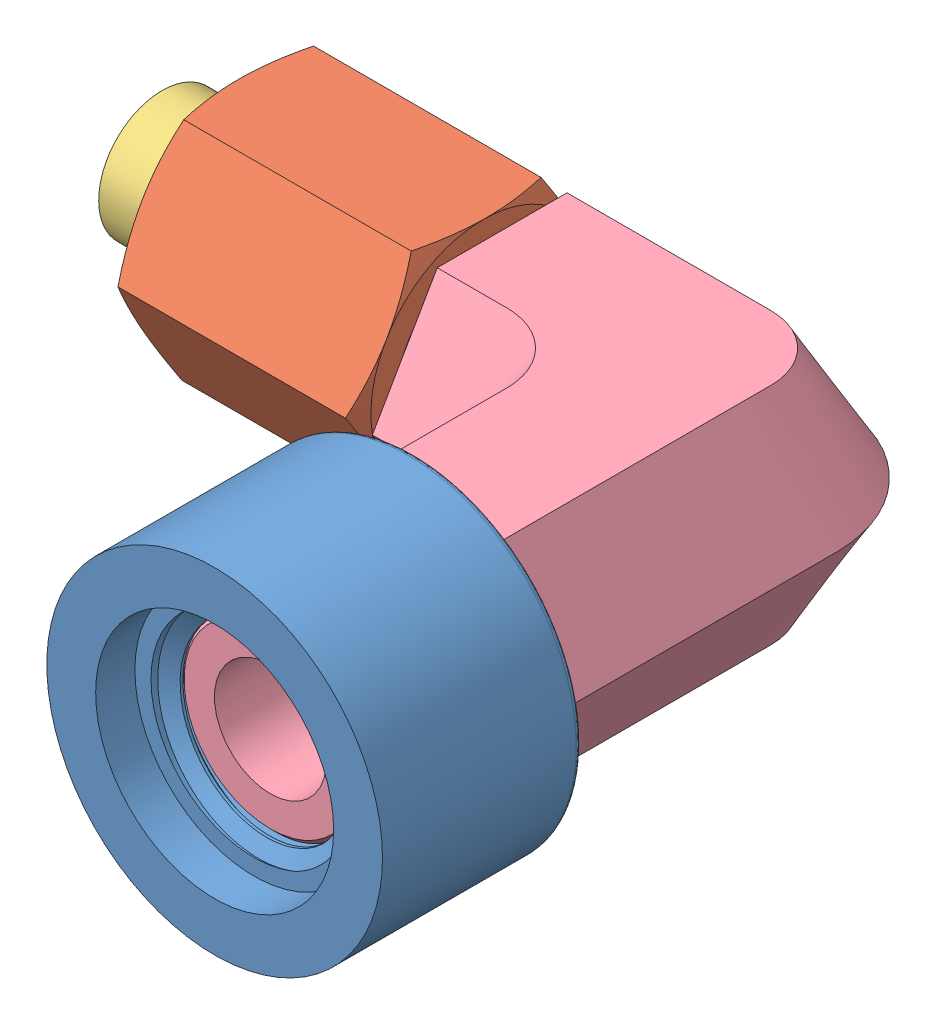
SolidWorks assembly Shroud Plumbing Connection Assem, configuration Default. Lengths in mm.
Overall size (45.23 21.34 39.53).
4 component instances, 4 part files, 9 mates.
Components (placement in the parent):
- 4452K139_TYPE 316 STAINLESS STL THREADED PIPE FITTING-1: 4452K139_TYPE 316 STAINLESS STL THREADED PIPE FITTING [4452K139] at (0 0 -6.35) x (-1 0 0) z (0 0 -1) size (21.34 21.34 12.7)
- 50715K324_37 DEGREE FLARED FITTING FOR SS TUBING-1: 50715K324_37 DEGREE FLARED FITTING FOR SS TUBING [50715K324] at (-29.6419 0 -31.226) x (0 0.999967 -0.008151) z (0 -0.008151 -0.999967) size (14.29 16.03 16.5)
- 50715K316_TYPE 316 SS 37 DEGREE FLARED TUBE FITTING-1: 50715K316_TYPE 316 SS 37 DEGREE FLARED TUBE FITTING [50715K316] at (-29.3561 0 -31.226) x (0 0 -1) z (1 0 0) size (9.65 9.65 10.41)
- 50715K182_37 DEGREE FLARED FITTING FOR STAINLESS STEEL TUBING-1: 50715K182_37 DEGREE FLARED FITTING FOR STAINLESS STEEL TUBING [50715K182] at (0 0 -31.226) x (1 0 0) z (0 -1 0) size (34.92 36.4 14.39)
Mates (geometry in assembly coordinates):
- Concentric9: concentric aligned: circle of 50715K324_37 DEGREE FLARED FITTING FOR SS TUBING-1; circle of 50715K316_TYPE 316 SS 37 DEGREE FLARED TUBE FITTING-1
- Coincident15: coincident anti-aligned: plane of 50715K324_37 DEGREE FLARED FITTING FOR SS TUBING-1 through (-27.7051 0.0393 -26.4002) normal (1 0 0); plane of 50715K316_TYPE 316 SS 37 DEGREE FLARED TUBE FITTING-1 through (-27.7051 4.0323 -31.226) normal (-1 0 0)
- Coincident17: coincident aligned: plane of 4452K139_TYPE 316 STAINLESS STL THREADED PIPE FITTING-1 through (0 0 -6.35) normal (0 1 0)
- Coincident18: coincident anti-aligned: plane of 4452K139_TYPE 316 STAINLESS STL THREADED PIPE FITTING-1 through (0 0 -6.35) normal (-1 0 0)
- Coincident19: coincident aligned: plane of 4452K139_TYPE 316 STAINLESS STL THREADED PIPE FITTING-1 through (0 0 0) normal (0 0 1)
- Concentric10: concentric anti-aligned: circle of 4452K139_TYPE 316 STAINLESS STL THREADED PIPE FITTING-1; circle of 50715K182_37 DEGREE FLARED FITTING FOR STAINLESS STEEL TUBING-1
- Distance2: distance = 1 mm anti-aligned: plane of 50715K182_37 DEGREE FLARED FITTING FOR STAINLESS STEEL TUBING-1 through (12.3733 7.1437 -13.7) normal (0 0 1); plane of 4452K139_TYPE 316 STAINLESS STL THREADED PIPE FITTING-1 through (0 0 -12.7) normal (0 0 -1)
- Concentric11: concentric aligned: circle of 50715K316_TYPE 316 SS 37 DEGREE FLARED TUBE FITTING-1; circle of 50715K182_37 DEGREE FLARED FITTING FOR STAINLESS STEEL TUBING-1
- Coincident21: coincident aligned: cone of 50715K316_TYPE 316 SS 37 DEGREE FLARED TUBE FITTING-1; cylinder of 50715K182_37 DEGREE FLARED FITTING FOR STAINLESS STEEL TUBING-1 through (-26.67 0 -31.226) axis (-1 0 0) radius 645.7718
